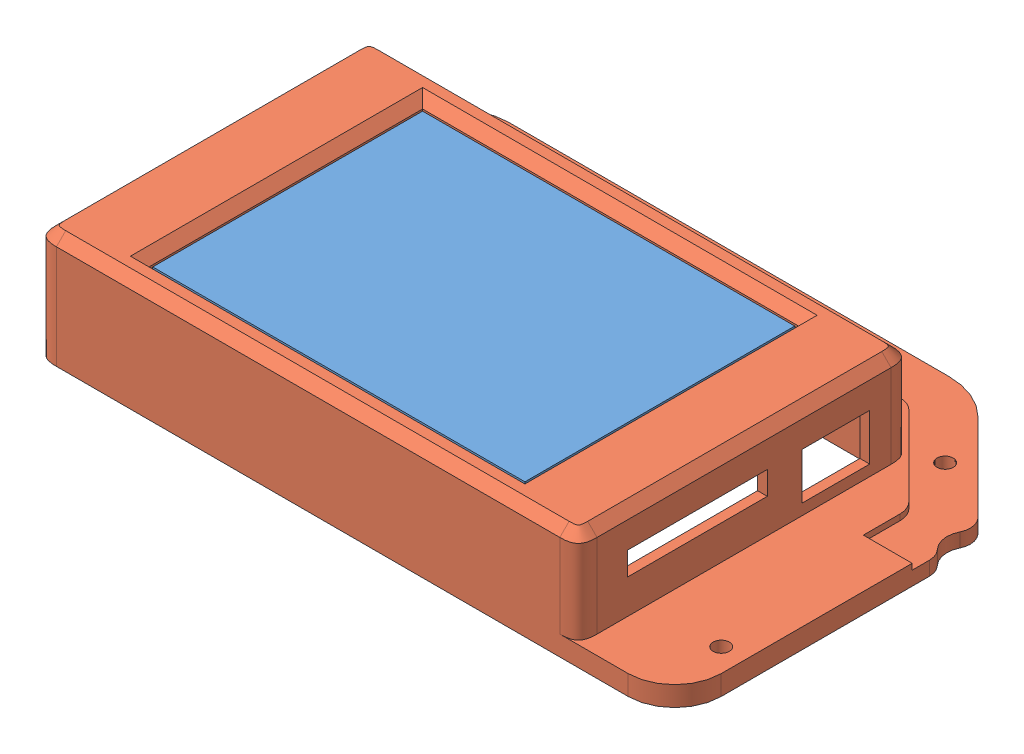
SolidWorks assembly SMW_MKS_TFT_ASMB_R3, configuration Default. Lengths in mm.
Overall size (136.89 24.27 91.05).
2 component instances, 2 part files, 6 mates.
Components (placement in the parent):
- MKS_TFT_R3-1: MKS_TFT_R3 [Default] x (1 0 0) z (0 1 0) size (110 65 6.6)
- Printed LCD Cover 2_R3-1: Printed LCD Cover 2_R3 [Default] at (0 -13 0) x (1 0 0) z (0 1 0) size (136.89 91.05 24.27)
Mates (geometry in assembly coordinates):
- Concentric3: concentric aligned: cylinder of MKS_TFT_R3-1 through (-51 75.6289 28.5) axis (0 1 0) radius 1.5; cylinder of Printed LCD Cover 2_R3-1 through (-51 77.2289 28.5) axis (0 1 0) radius 1.3
- Concentric4: concentric aligned: cylinder of MKS_TFT_R3-1 through (51 75.6289 -28.5) axis (0 1 0) radius 1.5; cylinder of Printed LCD Cover 2_R3-1 through (51 77.2289 -28.5) axis (0 1 0) radius 1.3
- Coincident2: coincident anti-aligned: plane of MKS_TFT_R3-1 through (0 77.2289 0) normal (0 1 0); plane of Printed LCD Cover 2_R3-1 through (51 77.2289 -28.5) normal (0 -1 0)
- Coincident3: coincident aligned: plane of ? through (0 77.2289 0) normal (1 0 0)
- Coincident4: coincident anti-aligned: plane of ? through (0 77.2289 0) normal (0 0 -1)
- Coincident5: coincident aligned: plane of MKS_TFT_R3-1 through (0 0 0) normal (0 1 0); plane of assembly
